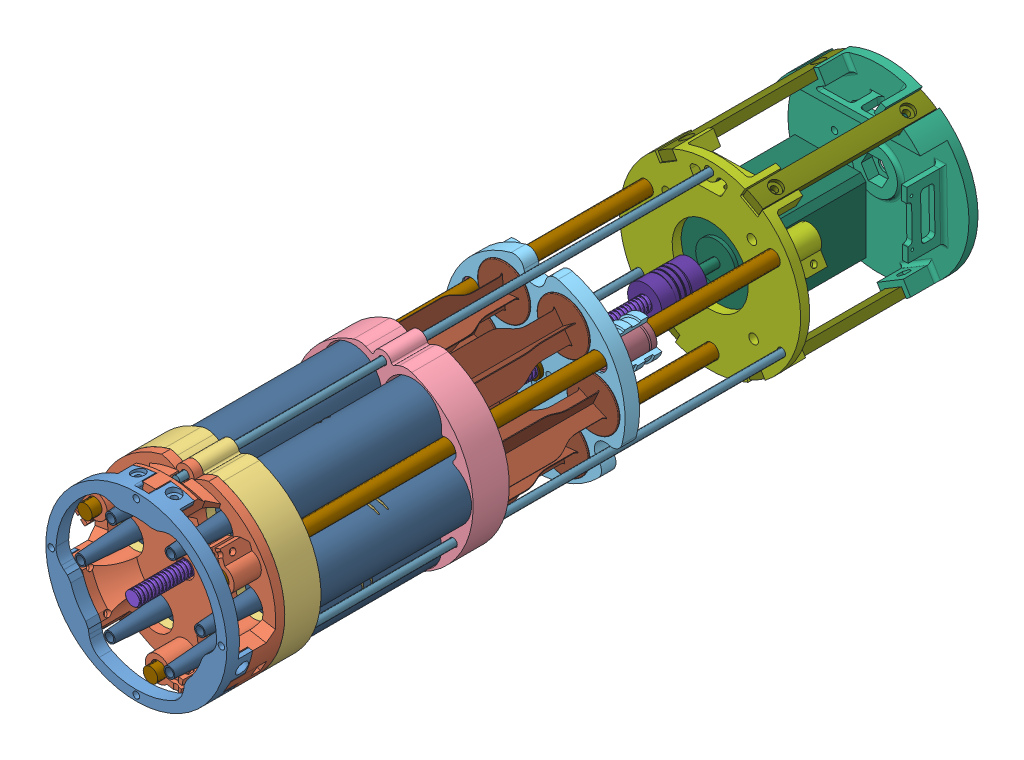
SolidWorks assembly Main Ballast Tank, configuration Default. Lengths in mm.
Overall size (104.09 101.96 419.5).
42 component instances, 18 part files, 43 mates.
Components (placement in the parent):
- Engine_endcap_mount-1: Engine_endcap_mount [默认] at (605.4001 -106.548 107.0395) x (-1 0 0) z (0 0 -1) size (100 100 15)
- Engine_end_connector-1: Engine_end_connector [默认] at (-444.5999 -106.548 75.0395) size (100 100 25)
- Syringe_clamp_front-2: Syringe_clamp_front [默认] at (155.4001 -106.548 75.0395) x (-1 0 0) z (0 0 -1) size (100 100 20)
- Syringe_clamp_back-1: Syringe_clamp_back [默认] at (-144.5999 43.452 -49.0312) size (100 100 20)
- Syringe_plunger_back-1: Syringe_plunger_back [默认] at (305.4001 43.452 -112.9677) x (-1 0 0) z (0 0 -1) size (100 98.49 25)
- Buoyancy_engine_bearing_plate-1: Buoyancy_engine_bearing_plate [默认] at (155.3708 46.4151 -307.9605) x (0.999805 0.019754 0) z (0 0 1) size (100 100 25)
- Buoyancy_engine_motor_mount-1: Buoyancy_engine_motor_mount [默认] at (308.3047 -100.5925 -209.9605) x (-0.999805 -0.019754 0) z (0 0 -1) size (100 100 20)
- 8mm_acme_300mm-1: 8mm_acme_300mm [默认] at (-114.5999 43.452 109.0395) x (1 0 0) z (0 -1 0) size (9.24 302.5 8)
- 8mm_smooth_rod_330mm-1: 8mm_smooth_rod_330mm [默认] at (-93.7998 2.9599 100.0395) x (1 0 0) z (0 -1 0) size (8 330 8)
- Syringe_barrel-1: Syringe_barrel [默认] at (-27.5999 43.452 -44.0312) x (1 0 0) z (0 -1 0) size (31.2 149 31.2)
- Syringe_plunger-1: Syringe_plunger [默认] at (-27.4985 43.188 -112.9677) x (0.913504 -0.40683 0) z (-0.40683 -0.913504 0) size (29 126.4 29)
- Syringe_plunger_rubber-1: Syringe_plunger_rubber [默认] at (-27.2521 42.5347 4.7123) x (1 0 0) z (0 0 -1) size (29.91 29.91 12.8)
- Syringe_plunger_rubber-2: Syringe_plunger_rubber [默认] at (-11.3881 71.0792 4.7123) x (0.5 -0.866025 0) z (0 0 -1) size (29.91 29.91 12.8)
- Syringe_plunger_rubber-3: Syringe_plunger_rubber [默认] at (21.2641 71.6127 4.7123) x (-0.5 -0.866025 0) z (0 0 -1) size (29.91 29.91 12.8)
- Syringe_plunger_rubber-4: Syringe_plunger_rubber [默认] at (38.0523 43.6019 4.7123) x (-1 0 0) z (0 0 -1) size (29.91 29.91 12.8)
- Syringe_plunger_rubber-5: Syringe_plunger_rubber [默认] at (22.1883 15.0574 4.7123) x (-0.5 0.866025 0) z (0 0 -1) size (29.91 29.91 12.8)
- Syringe_plunger_rubber-6: Syringe_plunger_rubber [默认] at (-10.4639 14.5239 4.7123) x (0.5 0.866025 0) z (0 0 -1) size (29.91 29.91 12.8)
- Syringe_plunger-2: Syringe_plunger [默认] at (-10.9456 71.6192 -112.9677) x (0.104427 -0.994533 0) z (-0.994533 -0.104427 0) size (29 126.4 29)
- Syringe_plunger-3: Syringe_plunger [默认] at (21.9531 71.4995 -112.9677) x (-0.809077 -0.587702 0) z (-0.587702 0.809077 0) size (29 126.4 29)
- Syringe_plunger-4: Syringe_plunger [默认] at (38.2988 42.9486 -112.9677) x (-0.913504 0.40683 0) z (0.40683 0.913504 0) size (29 126.4 29)
- Syringe_plunger-5: Syringe_plunger [默认] at (21.7458 14.5174 -112.9677) x (-0.104427 0.994533 0) z (0.994533 0.104427 0) size (29 126.4 29)
- Syringe_plunger-6: Syringe_plunger [默认] at (-11.1528 14.637 -112.9677) x (0.809077 0.587702 0) z (0.587702 -0.809077 0) size (29 126.4 29)
- Syringe_barrel-2: Syringe_barrel [默认] at (-10.7676 71.839 -44.0312) x (0.5 -0.866025 0) z (-0.866025 -0.5 0) size (31.2 149 31.2)
- Syringe_barrel-3: Syringe_barrel [默认] at (22.2324 71.4553 -44.0312) x (-0.5 -0.866025 0) z (-0.866025 0.5 0) size (31.2 149 31.2)
- Syringe_barrel-4: Syringe_barrel [默认] at (38.4001 42.6846 -44.0312) x (-1 0 0) z (0 1 0) size (31.2 149 31.2)
- Syringe_barrel-5: Syringe_barrel [默认] at (21.5678 14.2976 -44.0312) x (-0.5 0.866025 0) z (0.866025 0.5 0) size (31.2 149 31.2)
- Syringe_barrel-6: Syringe_barrel [默认] at (-11.4322 14.6813 -44.0312) x (0.5 0.866025 0) z (0.866025 -0.5 0) size (31.2 149 31.2)
- LM8UU-1: LM8UU [默认] at (40.4741 123.702 -137.9677) x (0 1 0) z (1 0 0) size (15 24 15)
- LM8UU-2: LM8UU [默认] at (-81.6354 33.702 -137.9677) x (-0.866025 -0.5 0) z (-0.5 0.866025 0) size (15 24 15)
- LM8UU-3: LM8UU [默认] at (57.3616 -27.048 -137.9677) x (0.866025 -0.5 0) z (-0.5 -0.866025 0) size (15 24 15)
- 4mm_threaded_rod_300mm-1: 4mm_threaded_rod_300mm [默认] at (5.4064 -111.548 85.0395) x (0 1 0) z (1 0 0) size (4 300 4)
- 4mm_threaded_rod_300mm-2: 4mm_threaded_rod_300mm [默认] at (139.6309 120.9575 85.0395) x (-0.866025 -0.5 0) z (-0.5 0.866025 0) size (4 300 4)
- 4mm_threaded_rod_300mm-3: 4mm_threaded_rod_300mm [默认] at (-128.837 120.9466 85.0395) x (0.866025 -0.5 0) z (-0.5 -0.866025 0) size (4 300 4)
- motors_17_42_60mm-1: motors_17_42_60mm [默认] at (5.4001 43.452 -269.9605) size (42.3 42.3 84)
- 8mm_smooth_rod_330mm-2: 8mm_smooth_rod_330mm [默认] at (90.0673 -22.2116 100.0395) x (-0.5 0.866025 0) z (0.866025 0.5 0) size (8 330 8)
- 8mm_smooth_rod_330mm-3: 8mm_smooth_rod_330mm [默认] at (19.9329 149.6078 100.0395) x (-0.5 -0.866025 0) z (-0.866025 0.5 0) size (8 330 8)
- Chassis_beam_buoyancy_engine-1: Chassis_beam_buoyancy_engine [默认] at (947.4909 -422.5422 -306.9605) x (-0.875733 0.482795 0) z (0.482795 0.875733 0) size (10 96 5)
- Chassis_beam_buoyancy_engine-2: Chassis_beam_buoyancy_engine [默认] at (-936.6906 509.4462 -306.9605) x (0.875733 -0.482795 0) z (-0.482795 -0.875733 0) size (10 96 5)
- Chassis_beam_buoyancy_engine-3: Chassis_beam_buoyancy_engine [默认] at (880.0083 626.3294 -306.9605) x (-0.855979 -0.51701 0) z (-0.51701 0.855979 0) size (10 96 5)
- Chassis_beam_buoyancy_engine-4: Chassis_beam_buoyancy_engine [默认] at (-869.2081 -539.4254 -306.9605) x (0.855979 0.51701 0) z (0.51701 -0.855979 0) size (10 96 5)
- Coupling_19_25_5_8mm-1: Coupling_19_25_5_8mm [默认] at (5.3281 43.4517 -198.9605) x (0.713357 0.700801 0) z (0.700801 -0.713357 0) size (20 25 19.06)
- Screw nut_8mm-1: Screw nut_8mm [默认] at (5.3281 43.4517 -120.9677) x (0.009005 -0.999959 0) z (-0.999959 -0.009005 0) size (22 15 22)
Mates (geometry in assembly coordinates):
- 同心1: concentric: cylinder of Engine_endcap_mount-1 through (5.4001 43.452 100.0395) axis (0 0 1) radius 44.419; cylinder of Engine_end_connector-1 through (5.4001 43.452 75.0395) axis (0 0 -1) radius 5
- 重合1: coincident: plane of Engine_endcap_mount-1 through (-44.5999 43.452 100.0395) normal (0 0 -1); plane of Engine_end_connector-1 through (5.4001 43.452 100.0395) normal (0 0 1)
- 同心2: concentric: cylinder of Engine_endcap_mount-1 through (5.4001 43.452 100.0395) axis (0 0 1) radius 50; cylinder of Syringe_clamp_front-2 through (5.4001 43.452 55.0395) axis (0 0 1) radius 50
- 同心3: concentric: cylinder of Syringe_clamp_front-2 through (5.4001 43.452 55.0395) axis (0 0 1) radius 50; cylinder of Syringe_clamp_back-1 through (5.4001 43.452 -29.0312) axis (0 0 -1) radius 50
- 同心4: concentric: cylinder of Syringe_clamp_back-1 through (5.4001 43.452 -29.0312) axis (0 0 -1) radius 50; cylinder of Syringe_plunger_back-1 through (5.4001 43.452 -120.9677) axis (0 0 1) radius 50
- 同心7: concentric: cylinder of Syringe_plunger_back-1 through (5.4001 43.452 -120.9677) axis (0 0 1) radius 50; cylinder of Buoyancy_engine_motor_mount-1 through (5.4001 43.452 -214.9605) axis (0 0 1) radius 50
- 同心8: concentric: cylinder of Buoyancy_engine_bearing_plate-1 through (5.4001 43.452 -307.9605) axis (0 0 1) radius 50; cylinder of Buoyancy_engine_motor_mount-1 through (5.4001 43.452 -214.9605) axis (0 0 1) radius 50
- 同心9: concentric: cylinder of Engine_end_connector-1 through (5.4001 43.452 75.0395) axis (0 0 -1) radius 5; cylinder of 8mm_acme_300mm-1 through (5.4001 43.452 -190.9605) axis (0 0 1) radius 4
- 同心10: concentric: cylinder of Buoyancy_engine_motor_mount-1 through (6.2002 2.9599 -229.9605) axis (0 0 1) radius 4.1; cylinder of 8mm_smooth_rod_330mm-1 through (6.2002 2.9599 -229.9605) axis (0 0 1) radius 4
- 重合3: coincident: plane of Buoyancy_engine_motor_mount-1 through (5.4001 43.452 -229.9605) normal (0 0 -1); plane of 8mm_smooth_rod_330mm-1 through (10.2002 2.9599 -229.9605) normal (0 0 -1)
- 重合4: coincident: plane of Engine_end_connector-1 through (5.4001 -6.548 75.0395) normal (0 0 -1); plane of Syringe_clamp_front-2 through (-2.8499 57.7414 75.0395) normal (0 0 1)
- 同心11: concentric: cylinder of Syringe_barrel-1 through (-27.5999 43.452 104.9688) axis (0 0 -1) radius 15.6; line of Syringe_plunger-1 through (-27.5999 43.452 6.0323) axis (0 0 -1)
- 重合5: coincident: point of Syringe_plunger-1; circle of Syringe_plunger_rubber-1
- 平行1: parallel: plane of Syringe_plunger-1 through (-27.4985 43.188 7.2323) normal (0 0 1); plane of Syringe_plunger_rubber-1 through (-17.5521 42.5347 4.7123) normal (0 0 -1)
- 同心12: concentric: cylinder of Syringe_clamp_front-2 through (-27.5999 43.452 55.0395) axis (0 0 1) radius 16.15; cylinder of Syringe_barrel-1 through (-27.5999 43.452 104.9688) axis (0 0 -1) radius 15.6
- 重合6: coincident: plane of Syringe_clamp_front-2 through (-30.9854 51.3304 70.0395) normal (0 0 -1); circle of Syringe_barrel-1
- 重合7: coincident: plane of Syringe_plunger_back-1 through (55.4001 43.952 -112.9677) normal (0 0 1); plane of Syringe_plunger-1 through (-27.4985 43.188 -112.9677) normal (0 0 -1)
- 重合8: coincident: plane of Syringe_clamp_back-1 through (30.4087 71.0063 -44.0312) normal (0 0 1); plane of Syringe_barrel-1 through (-13.0999 43.452 -44.0312) normal (0 0 -1)
- 同心13: concentric: cylinder of Syringe_plunger_back-1 through (40.4741 63.702 -112.9677) axis (0 0 -1) radius 7.65; cylinder of LM8UU-1 through (40.4741 63.702 -113.9677) axis (0 0 -1) radius 7.5
- 重合9: coincident: plane of Syringe_plunger_back-1 through (40.4741 63.702 -137.9677) normal (0 0 -1); plane of LM8UU-1 through (40.4741 67.702 -137.9677) normal (0 0 -1)
- 重合10: coincident: plane of Engine_end_connector-1 through (5.4001 88.452 85.0395) normal (0 0 -1); plane of 4mm_threaded_rod_300mm-1 through (5.4064 88.452 85.0395) normal (0 0 1)
- 同心14: concentric: cylinder of Syringe_clamp_back-1 through (5.4064 88.452 -49.0312) axis (0 0 -1) radius 2.25; cylinder of 4mm_threaded_rod_300mm-1 through (5.4064 88.452 -214.9605) axis (0 0 1) radius 2
- 重合11: coincident: plane of Engine_end_connector-1 through (5.4001 43.452 100.0395) normal (0 0 1); plane of 8mm_smooth_rod_330mm-1 through (6.2002 2.9599 100.0395) normal (0 0 1)
- 同心15: concentric: cylinder of Buoyancy_engine_motor_mount-1 through (5.4001 43.452 -209.9605) axis (0 0 1) radius 21; cylinder of motors_17_42_60mm-1 through (5.4001 43.452 -190.9605) axis (0 0 -1) radius 2.5
- 重合12: coincident: plane of Buoyancy_engine_motor_mount-1 through (6.3878 -6.5382 -214.9605) normal (0 0 -1); plane of motors_17_42_60mm-1 through (26.5501 64.602 -214.9605) normal (0 0 1)
- 同心16: concentric: circle of Buoyancy_engine_motor_mount-1; cylinder of Chassis_beam_buoyancy_engine-1 through (29.2985 86.8008 -222.4605) axis (0.482795 0.875733 0) radius 1.8
- 同心17: concentric: cylinder of Buoyancy_engine_bearing_plate-1 through (26.1603 81.1086 -295.4605) axis (-0.482795 -0.875733 0) radius 1.7; cylinder of Chassis_beam_buoyancy_engine-1 through (29.2985 86.8008 -295.4605) axis (0.482795 0.875733 0) radius 1.8
- 重合14: coincident: plane of Buoyancy_engine_motor_mount-1 through (31.701 79.7668 -209.9605) normal (0.482795 0.875733 0); plane of Chassis_beam_buoyancy_engine-1 through (22.5058 84.8361 -306.9605) normal (-0.482795 -0.875733 0)
- 同心22: concentric: cylinder of Buoyancy_engine_bearing_plate-1 through (27.6315 6.6449 -295.4605) axis (-0.51701 0.855979 0) radius 1.7; cylinder of Chassis_beam_buoyancy_engine-4 through (30.9921 1.081 -295.4605) axis (0.51701 -0.855979 0) radius 1.8
- 同心23: concentric: cylinder of Buoyancy_engine_motor_mount-1 through (27.6315 6.6449 -222.4605) axis (-0.51701 0.855979 0) radius 1.7; cylinder of Chassis_beam_buoyancy_engine-4 through (30.9921 1.081 -222.4605) axis (0.51701 -0.855979 0) radius 1.8
- 同心24: concentric: cylinder of Buoyancy_engine_motor_mount-1 through (27.6315 6.6449 -222.4605) axis (-0.51701 0.855979 0) radius 1.7; cylinder of Chassis_beam_buoyancy_engine-4 through (30.9921 1.081 -222.4605) axis (0.51701 -0.855979 0) radius 1.8
- 重合17: coincident: plane of Buoyancy_engine_motor_mount-1 through (23.6992 2.5174 -209.9605) normal (0.51701 -0.855979 0); plane of Chassis_beam_buoyancy_engine-4 through (32.687 7.946 -306.9605) normal (-0.51701 0.855979 0)
- 重合18: coincident: plane of Buoyancy_engine_bearing_plate-1 through (-11.2677 1.8265 -307.9605) normal (-0.482795 -0.875733 0); plane of Chassis_beam_buoyancy_engine-2 through (-11.7056 2.0679 -306.9605) normal (0.482795 0.875733 0)
- 同心25: concentric: cylinder of Buoyancy_engine_bearing_plate-1 through (-15.3601 5.7955 -295.4605) axis (0.482795 0.875733 0) radius 1.7; cylinder of Chassis_beam_buoyancy_engine-2 through (-18.4982 0.1032 -295.4605) axis (-0.482795 -0.875733 0) radius 1.8
- 同心26: concentric: cylinder of Buoyancy_engine_motor_mount-1 through (-15.3601 5.7955 -222.4605) axis (0.482795 0.875733 0) radius 1.7; cylinder of Chassis_beam_buoyancy_engine-2 through (-18.4982 0.1032 -222.4605) axis (-0.482795 -0.875733 0) radius 1.8
- 重合19: coincident: plane of Buoyancy_engine_motor_mount-1 through (-12.8989 84.3867 -209.9605) normal (-0.51701 0.855979 0); plane of Chassis_beam_buoyancy_engine-3 through (-21.8867 78.9581 -306.9605) normal (0.51701 -0.855979 0)
- 同心27: concentric: cylinder of Buoyancy_engine_bearing_plate-1 through (-16.8313 80.2591 -295.4605) axis (0.51701 -0.855979 0) radius 1.7; cylinder of Chassis_beam_buoyancy_engine-3 through (-20.1919 85.823 -295.4605) axis (-0.51701 0.855979 0) radius 1.8
- 同心28: concentric: cylinder of Buoyancy_engine_motor_mount-1 through (-16.8313 80.2591 -222.4605) axis (0.51701 -0.855979 0) radius 1.7; cylinder of Chassis_beam_buoyancy_engine-3 through (-20.1919 85.823 -222.4605) axis (-0.51701 0.855979 0) radius 1.8
- 重合23: coincident: plane of motors_17_42_60mm-1 through (7.9001 43.452 -190.9605) normal (0 0 1); plane of Coupling_19_25_5_8mm-1
- 重合24: coincident: plane of 8mm_acme_300mm-1 through (9.4001 43.452 -190.9605) normal (0 0 -1); plane of Coupling_19_25_5_8mm-1
- 同心29: concentric: cylinder of Coupling_19_25_5_8mm-1 through (5.3281 43.4517 -173.9605) axis (0 0 -1) radius 9.5; cylinder of Screw nut_8mm-1 through (5.3281 43.4517 -140.4702) axis (0 0 1) radius 5.1
- 同心30: concentric: cylinder of Syringe_plunger_back-1 through (5.4001 35.452 -107.9677) axis (0 0 -1) radius 1.75; cylinder of Screw nut_8mm-1 through (5.4001 35.452 -126.4677) axis (0 0 1) radius 1.75
- 重合25: coincident: plane of Syringe_plunger_back-1 through (5.4001 43.452 -120.9677) normal (0 0 -1); plane of Screw nut_8mm-1 through (5.3281 43.4517 -120.9677) normal (0 0 1)
